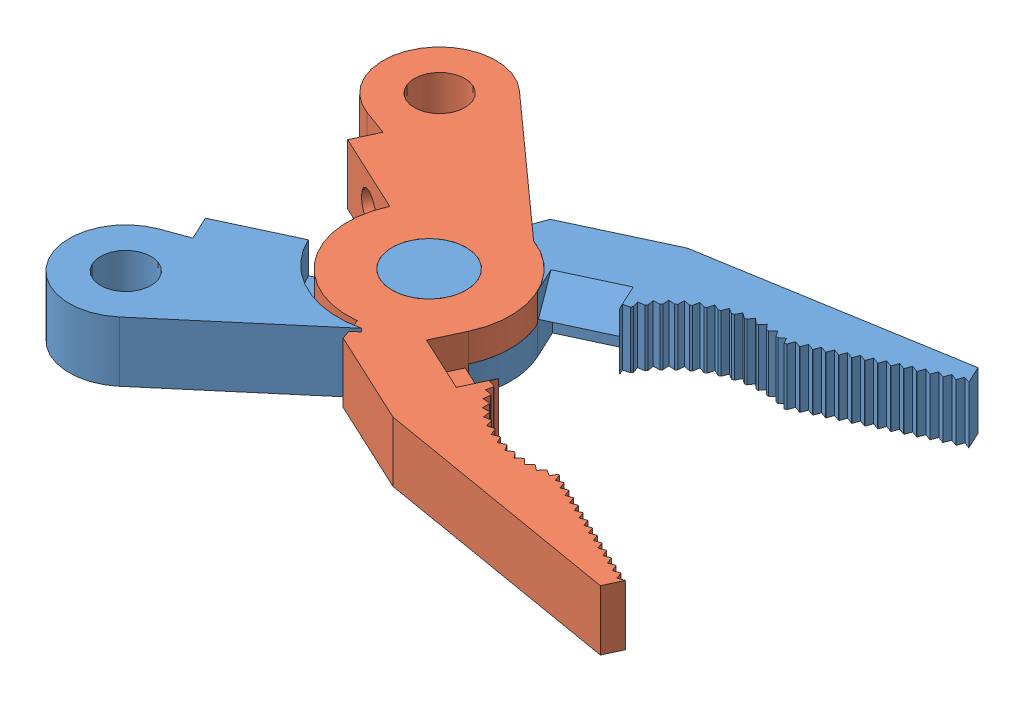
SolidWorks assembly Needle Nose, configuration Default. Lengths in mm.
Overall size (55.83 5.08 40.15).
2 component instances, 2 part files, 10 mates.
Components (placement in the parent):
- Needle Nose 2-1: Needle Nose 2 [Default] at (0 -2.286 0) x (0.906308 0 -0.422618) z (0.422618 0 0.906308) size (53.18 4.83 17.91)
- Needle Nose 1-1: Needle Nose 1 [Default] at (0 2.286 0) x (0.906308 0 0.422618) z (0.422618 0 -0.906308) size (53.23 4.83 17.94)
Mates (geometry in assembly coordinates):
- Concentric1: concentric anti-aligned: cylinder of Needle Nose 2-1 through (0 2.286 0) axis (0 -1 0) radius 2.9845; cylinder of Needle Nose 1-1 through (0 -2.54 0) axis (0 1 0) radius 2.9845
- Parallel2: parallel: plane of Needle Nose 2-1 through (0 2.286 0) normal (0 1 0); plane of Needle Nose 1-1 through (0 2.286 0) normal (0 1 0)
- Coincident4: coincident anti-aligned: plane of Needle Nose 2-1 through (0 0 0) normal (0 1 0); plane of Needle Nose 1-1 through (0 0 0) normal (0 -1 0)
- Coincident7: coincident anti-aligned: line of Needle Nose 2-1 through (2.286 0 0) axis (0 0 1)
- Coincident9: coincident aligned: line of Needle Nose 2-1 through (2.286 0 0) axis (0 0 -1)
- Coincident10: coincident aligned: line of Needle Nose 1-1 through (0 -0.0318 0) axis (0 -1 0)
- Coincident11: coincident anti-aligned: plane of Needle Nose 1-1 through (0 0 0) normal (0 -1 0)
- Coincident12: coincident aligned: plane of Needle Nose 2-1 through (0 0 0) normal (0 1 0)
- Symmetric1: symmetric aligned: plane of Needle Nose 1-1 through (0 2.286 0) normal (0.422618 0 -0.906308); plane of Needle Nose 2-1 through (0 -2.286 0) normal (0.422618 0 0.906308)
- LimitAngle2: limit planar angle = 0.436332 rad: plane of assembly through (0 0 0) normal (0 0 1); plane of assembly; plane of Needle Nose 2-1 through (0 -2.286 0) normal (0.422618 0 0.906308)
